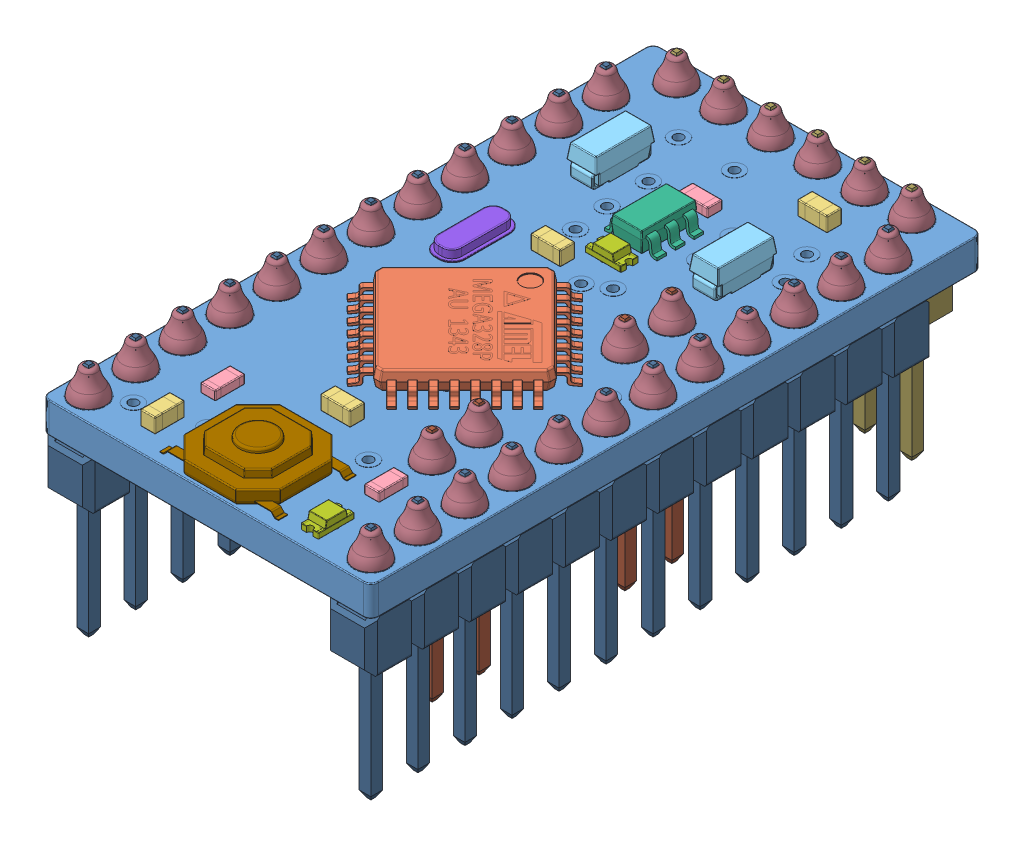
SolidWorks assembly ASSEMBLY, configuration Default. Lengths in mm.
Overall size (17.78 12.75 33.02).
56 component instances, 13 part files, 84 mates.
Components (placement in the parent):
- board-1: board [Default] at (5.4752 15.0552 41.6975) size (17.78 1.67 33.02)
- ATmega-1: ATmega [Default] at (14.3652 16.8027 27.7275) x (0.707107 0 0.707107) z (-0.707107 0 0.707107) size (9 1.1 9)
- cap_603-1: cap_603 [Default] at (10.3417 16.7052 40.4401) x (0 0 -1) z (1 0 0) size (1.6 0.8 0.8)
- cap_603-2: cap_603 [Default] at (13.6922 16.7052 34.8585) size (1.6 0.8 0.8)
- cap_603-3: cap_603 [Default] at (11.8634 16.7052 21.6759) size (1.6 0.8 0.8)
- cap_603-4: cap_603 [Default] at (17.4768 16.7052 12.8875) size (1.6 0.8 0.8)
- res_603-1: res_603 [Default] at (10.4218 16.7052 37.2651) x (0 0 -1) z (1 0 0) size (1.6 0.5 0.8)
- res_603-2: res_603 [Default] at (19.5912 16.7052 37.5953) x (0 0 -1) z (1 0 0) size (1.6 0.5 0.8)
- res_603-3: res_603 [Default] at (15.1652 16.7052 14.6275) x (-1 0 0) z (0 0 -1) size (1.6 0.5 0.8)
- condensateurTantale_106C-1: condensateurTantale_106C [Défaut] at (10.1742 17.5052 15.6625) x (0 0 -1) z (1 0 0) size (3.2 1.6 1.6)
- condensateurTantale_106C-2: condensateurTantale_106C [Défaut] at (18.6832 17.5052 17.5675) x (0 0 -1) z (1 0 0) size (3.2 1.6 1.6)
- SOT23-5-1: SOT23-5 [Default] at (14.3653 16.6848 17.5167) x (1 0 0) z (0 1 0) size (2.91 3.01 1.23)
- Surface Mount Chip LED 3.2x1.6mm-1: Surface Mount Chip LED 3.2x1.6mm [Default] at (18.7112 16.7112 39.0103) x (0 0 1) z (0 1 0) size (1.92 0.96 0.72)
- Surface Mount Chip LED 3.2x1.6mm-2: Surface Mount Chip LED 3.2x1.6mm [Default] at (13.4306 16.7112 20.3081) x (1 0 0) z (0 1 0) size (1.92 0.96 0.72)
- Crystal_Low_Profile-1: Crystal_Low_Profile [Default] at (9.717 16.7052 22.6754) x (0 0 -1) z (0 1 0) size (3.84 1.66 0.85)
  - Fusion001-1: Fusion001 [Default] at origin size (3.84 1.66 0.85)
- TACTILE-SWITCH-SMD-ALT01-1: TACTILE-SWITCH-SMD-ALT01 [Default] at (14.4922 16.7052 39.0305) size (6.4 1.4 5.25)
- Pin Header 1x12 TH Pitch 2.54mm-1: Pin Header 1x12 TH Pitch 2.54mm [Default] at (6.7452 15.0555 40.428) x (0 0.000074 -1) z (0 -1 -0.000074) size (30.48 2.54 12.7)
- Pin Header 1x12 TH Pitch 2.54mm-2: Pin Header 1x12 TH Pitch 2.54mm [Default] at (21.9852 15.0555 40.428) x (0 0.000074 -1) z (0 -1 -0.000074) size (30.48 2.54 12.7)
- Pin Header 1x2 TH Pitch 2.54mm-1: Pin Header 1x2 TH Pitch 2.54mm [Default] at (19.0642 15.0566 31.6645) x (0 0 1) z (0 -1 0) size (5.08 2.54 12.7)
- Pin Header 1x2 TH Pitch 2.54mm-2: Pin Header 1x2 TH Pitch 2.54mm [Default] at (19.0642 15.0565 21.2505) x (0 0.000074 1) z (0 -1 0.000074) size (5.08 2.54 12.7)
- Pin Header 1x6 TH Pitch 2.54mm-1: Pin Header 1x6 TH Pitch 2.54mm [Default] at (8.0152 15.0566 9.9475) x (1 0 0) z (0 -1 0) size (15.24 2.54 12.7)
- solder-1: solder [Default] at (6.7452 16.7152 40.4275) size (1.8 1.45 1.8)
- solder-13: solder [Default] at (21.9852 16.7152 40.4275) size (1.8 1.45 1.8)
- solder-25: solder [Default] at (19.0642 16.7152 23.7905) size (1.8 1.45 1.8)
- solder-37: solder [Default] at (19.0642 16.7152 34.2045) size (1.8 1.45 1.8)
- solder-39: solder [Default] at (20.7152 16.7152 9.9475) size (1.8 1.45 1.8)
- solder-2: solder [Default] at (6.7452 16.7152 37.8875) size (1.8 1.45 1.8)
- solder-3: solder [Default] at (6.7452 16.7152 35.3475) size (1.8 1.45 1.8)
- solder-4: solder [Default] at (6.7452 16.7152 32.8075) size (1.8 1.45 1.8)
- solder-5: solder [Default] at (6.7452 16.7152 30.2675) size (1.8 1.45 1.8)
- solder-6: solder [Default] at (6.7452 16.7152 27.7275) size (1.8 1.45 1.8)
- solder-7: solder [Default] at (6.7452 16.7152 25.1875) size (1.8 1.45 1.8)
- solder-8: solder [Default] at (6.7452 16.7152 22.6475) size (1.8 1.45 1.8)
- solder-9: solder [Default] at (6.7452 16.7152 20.1075) size (1.8 1.45 1.8)
- solder-10: solder [Default] at (6.7452 16.7152 17.5675) size (1.8 1.45 1.8)
- solder-11: solder [Default] at (6.7452 16.7152 15.0275) size (1.8 1.45 1.8)
- solder-12: solder [Default] at (6.7452 16.7152 12.4875) size (1.8 1.45 1.8)
- solder-14: solder [Default] at (21.9852 16.7152 37.8875) size (1.8 1.45 1.8)
- solder-15: solder [Default] at (21.9852 16.7152 35.3475) size (1.8 1.45 1.8)
- solder-16: solder [Default] at (21.9852 16.7152 32.8075) size (1.8 1.45 1.8)
- solder-17: solder [Default] at (21.9852 16.7152 30.2675) size (1.8 1.45 1.8)
- solder-18: solder [Default] at (21.9852 16.7152 27.7275) size (1.8 1.45 1.8)
- solder-19: solder [Default] at (21.9852 16.7152 25.1875) size (1.8 1.45 1.8)
- solder-20: solder [Default] at (21.9852 16.7152 22.6475) size (1.8 1.45 1.8)
- solder-21: solder [Default] at (21.9852 16.7152 20.1075) size (1.8 1.45 1.8)
- solder-22: solder [Default] at (21.9852 16.7152 17.5675) size (1.8 1.45 1.8)
- solder-23: solder [Default] at (21.9852 16.7152 15.0275) size (1.8 1.45 1.8)
- solder-24: solder [Default] at (21.9852 16.7152 12.4875) size (1.8 1.45 1.8)
- solder-26: solder [Default] at (19.0642 16.7152 21.2505) size (1.8 1.45 1.8)
- solder-38: solder [Default] at (19.0642 16.7152 31.6645) size (1.8 1.45 1.8)
- solder-40: solder [Default] at (18.1752 16.7152 9.9475) size (1.8 1.45 1.8)
- solder-41: solder [Default] at (15.6352 16.7152 9.9475) size (1.8 1.45 1.8)
- solder-42: solder [Default] at (13.0952 16.7152 9.9475) size (1.8 1.45 1.8)
- solder-43: solder [Default] at (10.5552 16.7152 9.9475) size (1.8 1.45 1.8)
- solder-44: solder [Default] at (8.0152 16.7152 9.9475) size (1.8 1.45 1.8)
Mates (geometry in assembly coordinates):
- Coincident2: coincident: plane of board-1 through (5.4752 16.7052 41.6975) normal (0 1 0); line of ATmega-1 through (9.1114 16.7052 26.6704) axis (0.707107 0 -0.707107)
- Coincident3: coincident: plane of board-1 through (5.4752 16.7052 41.6975) normal (0 1 0); line of ATmega-1 through (17.3563 16.7052 31.0474) axis (-0.707107 0 0.707107)
- Angle3: planar angle = 0.785398 rad aligned: plane of ATmega-1 through (9.6576 17.2252 26.7146) normal (-0.707107 0 -0.707107); plane of board-1 through (5.4752 16.7052 41.6975) normal (-1 0 0)
- Distance1: distance = 13.97 mm: point of ATmega-1; plane of board-1 through (5.4752 16.7052 41.6975) normal (0 0 1)
- Distance2: distance = 8.89 mm: point of ATmega-1; plane of board-1 through (5.4752 16.7052 41.6975) normal (-1 0 0)
- Parallel1: parallel aligned: plane of board-1 through (23.2552 16.7052 41.6975) normal (1 0 0); plane of cap_603-1 through (10.3417 17.5052 40.0401) normal (1 0 0)
- Distance6: distance = 4.5466 mm: point of cap_603-1; line of board-1 through (5.4752 16.6552 41.2975) axis (0 0 -1)
- Parallel2: parallel aligned: plane of board-1 through (5.4752 16.7052 41.6975) normal (0 0 1); plane of cap_603-2 through (14.0922 17.5052 34.8585) normal (0 0 1)
- Coincident11: coincident anti-aligned: plane of board-1 through (5.4752 16.7052 41.6975) normal (0 1 0); plane of cap_603-1 through (10.3417 16.7052 40.4401) normal (0 -1 0)
- Distance8: distance = 2.0574 mm: point of cap_603-1; plane of board-1 through (5.4752 16.7052 41.6975) normal (0 0 1)
- Coincident13: coincident anti-aligned: plane of board-1 through (5.4752 16.7052 41.6975) normal (0 1 0); plane of cap_603-2 through (13.6922 16.7052 34.8585) normal (0 -1 0)
- Distance9: distance = 7.239 mm: point of cap_603-2; plane of board-1 through (5.4752 16.7052 41.6975) normal (0 0 1)
- Distance10: distance = 9.017 mm: plane of board-1 through (5.4752 16.7052 41.6975) normal (-1 0 0); point of cap_603-2
- Coincident17: coincident anti-aligned: plane of board-1 through (5.4752 16.7052 41.6975) normal (0 1 0); plane of cap_603-3 through (11.8634 16.7052 21.6759) normal (0 -1 0)
- Parallel4: parallel aligned: plane of board-1 through (5.4752 16.7052 41.6975) normal (-1 0 0); plane of cap_603-3 through (11.8634 17.5052 21.6759) normal (-1 0 0)
- Distance11: distance = 7.1882 mm: point of cap_603-3; plane of board-1 through (5.4752 16.7052 41.6975) normal (-1 0 0)
- Distance12: distance = 20.4216 mm: point of cap_603-3; plane of board-1 through (5.4752 16.7052 41.6975) normal (0 0 1)
- Coincident21: coincident anti-aligned: plane of board-1 through (5.4752 16.7052 41.6975) normal (0 1 0); plane of cap_603-4 through (17.4768 16.7052 12.8875) normal (0 -1 0)
- Parallel5: parallel aligned: plane of board-1 through (5.4752 16.7052 41.6975) normal (-1 0 0); plane of cap_603-4 through (17.4768 17.5052 12.8875) normal (-1 0 0)
- Distance13: distance = 12.8016 mm: point of cap_603-4; plane of board-1 through (5.4752 16.7052 41.6975) normal (-1 0 0)
- Distance14: distance = 29.21 mm: point of cap_603-4; plane of board-1 through (5.4752 16.7052 41.6975) normal (0 0 1)
- Parallel6: parallel anti-aligned: plane of board-1 through (5.4752 16.7052 41.6975) normal (-1 0 0); plane of res_603-1 through (10.4218 17.2052 36.9651) normal (1 0 0)
- Distance15: distance = 5.2324 mm: point of res_603-1; plane of board-1 through (5.4752 16.7052 41.6975) normal (0 0 1)
- Coincident27: coincident anti-aligned: plane of board-1 through (5.4752 16.7052 41.6975) normal (0 1 0); plane of res_603-1 through (10.4218 16.7052 37.2651) normal (0 -1 0)
- Distance16: distance = 4.5466 mm: point of res_603-1; plane of board-1 through (5.4752 16.7052 41.6975) normal (-1 0 0)
- Parallel7: parallel aligned: plane of board-1 through (5.4752 16.7052 41.6975) normal (-1 0 0); plane of res_603-2 through (18.7912 17.2052 37.2953) normal (-1 0 0)
- Coincident30: coincident anti-aligned: plane of board-1 through (5.4752 16.7052 41.6975) normal (0 1 0); plane of res_603-2 through (19.5912 16.7052 37.5953) normal (0 -1 0)
- Distance17: distance = 13.716 mm: point of res_603-2; plane of board-1 through (5.4752 16.7052 41.6975) normal (-1 0 0)
- Distance18: distance = 4.9022 mm: point of res_603-2; plane of board-1 through (5.4752 16.7052 41.6975) normal (0 0 1)
- Coincident33: coincident anti-aligned: plane of board-1 through (5.4752 16.7052 41.6975) normal (0 1 0); plane of res_603-3 through (15.1652 16.7052 14.6275) normal (0 -1 0)
- Parallel9: parallel anti-aligned: plane of board-1 through (23.2552 16.7052 41.6975) normal (1 0 0); plane of res_603-3 through (13.5652 17.2052 15.4275) normal (-1 0 0)
- Distance19: distance = 8.89 mm: point of res_603-3; plane of board-1 through (5.4752 16.7052 41.6975) normal (-1 0 0)
- Distance20: distance = 26.67 mm: point of res_603-3; plane of board-1 through (5.4752 16.7052 41.6975) normal (0 0 1)
- Coincident34: coincident anti-aligned: plane of board-1 through (5.4752 16.7052 41.6975) normal (0 1 0); plane of condensateurTantale_106C-1 through (10.7742 16.7052 14.2125) normal (0 -1 0)
- Distance21: distance = 4.699 mm: point of condensateurTantale_106C-1; plane of board-1 through (5.4752 16.7052 41.6975) normal (-1 0 0)
- Distance22: distance = 26.035 mm: point of condensateurTantale_106C-1; plane of board-1 through (5.4752 16.7052 41.6975) normal (0 0 1)
- Parallel16: parallel anti-aligned: line of board-1 through (5.4752 16.6552 41.2975) axis (0 0 -1); line of condensateurTantale_106C-1 through (9.375 17.5114 14.2979) axis (0 0 1)
- Coincident42: coincident anti-aligned: plane of board-1 through (5.4752 16.7052 41.6975) normal (0 1 0); plane of condensateurTantale_106C-2 through (19.2832 16.7052 19.0175) normal (0 -1 0)
- Parallel17: parallel anti-aligned: line of board-1 through (5.4752 16.6552 41.2975) axis (0 0 -1); line of condensateurTantale_106C-2 through (17.884 17.5114 16.2029) axis (0 0 1)
- Distance23: distance = 13.208 mm: point of condensateurTantale_106C-2; plane of board-1 through (5.4752 16.7052 41.6975) normal (-1 0 0)
- Distance24: distance = 24.13 mm: point of condensateurTantale_106C-2; plane of board-1 through (5.4752 16.7052 41.6975) normal (0 0 1)
- Coincident50: coincident: plane of board-1 through (5.4752 16.7052 41.6975) normal (0 1 0); line of SOT23-5-1 through (12.9501 16.7052 16.7667) axis (0 0 -1)
- Coincident51: coincident: plane of board-1 through (5.4752 16.7052 41.6975) normal (0 1 0); line of SOT23-5-1 through (15.7804 16.7052 16.2667) axis (0 0 1)
- Parallel23: parallel aligned: line of board-1 through (5.5252 16.7052 9.0775) axis (0 0 1); line of SOT23-5-1 through (13.5402 17.5131 16.0666) axis (0 0 1)
- Distance25: distance = 8.89 mm: point of SOT23-5-1; plane of board-1 through (5.4752 16.7052 41.6975) normal (-1 0 0)
- Distance26: distance = 24.1808 mm: point of SOT23-5-1; plane of board-1 through (5.4752 16.7052 41.6975) normal (0 0 1)
- Coincident55: coincident anti-aligned: plane of board-1 through (5.4752 16.7052 41.6975) normal (0 1 0); plane of Surface Mount Chip LED 3.2x1.6mm-1 through (18.8312 16.7052 39.0103) normal (0 -1 0)
- Parallel24: parallel anti-aligned: plane of board-1 through (5.4752 16.7052 41.6975) normal (-1 0 0); plane of Surface Mount Chip LED 3.2x1.6mm-1 through (19.6712 16.7112 40.9303) normal (1 0 0)
- Distance27: distance = 1.7272 mm: point of Surface Mount Chip LED 3.2x1.6mm-1; plane of board-1 through (5.4752 16.7052 41.6975) normal (0 0 1)
- Distance28: distance = 13.716 mm: point of Surface Mount Chip LED 3.2x1.6mm-1; plane of board-1 through (5.4752 16.7052 41.6975) normal (-1 0 0)
- Coincident59: coincident anti-aligned: plane of board-1 through (5.4752 16.7052 41.6975) normal (0 1 0); plane of Surface Mount Chip LED 3.2x1.6mm-2 through (13.4306 16.7052 20.1881) normal (0 -1 0)
- Parallel25: parallel anti-aligned: plane of board-1 through (5.4752 16.7052 41.6975) normal (-1 0 0); plane of Surface Mount Chip LED 3.2x1.6mm-2 through (15.3506 16.7112 20.3081) normal (1 0 0)
- Distance29: distance = 8.9154 mm: point of Surface Mount Chip LED 3.2x1.6mm-2; plane of board-1 through (5.4752 16.7052 41.6975) normal (-1 0 0)
- Distance30: distance = 21.8694 mm: point of Surface Mount Chip LED 3.2x1.6mm-2; plane of board-1 through (5.4752 16.7052 41.6975) normal (0 0 1)
- Coincident63: coincident anti-aligned: plane of board-1 through (5.4752 16.7052 41.6975) normal (0 1 0); plane of Crystal_Low_Profile-1/Fusion001-1 through (8.9033 16.7052 24.5829) normal (0 -1 0)
- Parallel26: parallel anti-aligned: plane of board-1 through (5.4752 16.7052 41.6975) normal (-1 0 0); plane of Crystal_Low_Profile-1/Fusion001-1 through (10.347 16.7652 20.9342) normal (1 0 0)
- Distance31: distance = 4.2418 mm: point of Crystal_Low_Profile-1/Fusion001-1; plane of board-1 through (5.4752 16.7052 41.6975) normal (-1 0 0)
- Distance32: distance = 19.0246 mm: point of Crystal_Low_Profile-1/Fusion001-1; plane of board-1 through (5.4752 16.7052 41.6975) normal (0 0 1)
- Parallel27: parallel anti-aligned: line of board-1 through (5.8752 16.7052 41.6475) axis (1 0 0); line of TACTILE-SWITCH-SMD-ALT01-1 through (15.8663 17.5052 41.568) axis (-1 0 0)
- Coincident68: coincident anti-aligned: plane of board-1 through (5.4752 16.7052 41.6975) normal (0 1 0); plane of TACTILE-SWITCH-SMD-ALT01-1 through (11.4609 16.7052 40.6305) normal (0 -1 0)
- Distance33: distance = 2.667 mm: point of TACTILE-SWITCH-SMD-ALT01-1; plane of board-1 through (5.4752 16.7052 41.6975) normal (0 0 1)
- Distance34: distance = 9.017 mm: point of TACTILE-SWITCH-SMD-ALT01-1; plane of board-1 through (5.4752 16.7052 41.6975) normal (-1 0 0)
- Coincident77: coincident aligned: plane of board-1 through (5.4752 16.7052 41.6975) normal (0 0 1); plane of Pin Header 1x12 TH Pitch 2.54mm-1 through (5.8022 12.5824 41.6975) normal (0 0 1)
- Coincident78: coincident aligned: plane of board-1 through (5.4752 16.7052 41.6975) normal (-1 0 0); plane of Pin Header 1x12 TH Pitch 2.54mm-1 through (5.4752 15.0831 39.4845) normal (-1 0 0)
- Coincident79: coincident anti-aligned: plane of board-1 through (5.4752 15.0552 41.6975) normal (0 -1 0); plane of Pin Header 1x12 TH Pitch 2.54mm-1 through (5.4652 15.0552 39.6305) normal (0 1 0)
- Coincident84: coincident aligned: plane of board-1 through (5.4752 16.7052 41.6975) normal (0 0 1); plane of Pin Header 1x12 TH Pitch 2.54mm-2 through (21.0422 12.5824 41.6975) normal (0 0 1)
- Coincident85: coincident aligned: plane of board-1 through (23.2552 16.7052 41.6975) normal (1 0 0); plane of Pin Header 1x12 TH Pitch 2.54mm-2 through (23.2552 15.0831 39.4845) normal (1 0 0)
- Coincident86: coincident anti-aligned: plane of board-1 through (5.4752 15.0552 41.6975) normal (0 -1 0); plane of Pin Header 1x12 TH Pitch 2.54mm-2 through (23.2652 15.0552 39.6305) normal (0 1 0)
- Distance36: distance = 14.859 mm anti-aligned: plane of Pin Header 1x2 TH Pitch 2.54mm-1 through (20.3342 15.0832 32.608) normal (1 0 0); plane of board-1 through (5.4752 16.7052 41.6975) normal (-1 0 0)
- Coincident89: coincident anti-aligned: plane of board-1 through (5.4752 15.0552 41.6975) normal (0 -1 0); plane of Pin Header 1x2 TH Pitch 2.54mm-1 through (20.3442 15.0552 33.4075) normal (0 1 0)
- Distance38: distance = 6.223 mm aligned: plane of Pin Header 1x2 TH Pitch 2.54mm-1 through (20.0072 12.5824 35.4745) normal (0 0 1); plane of board-1 through (5.4752 16.7052 41.6975) normal (0 0 1)
- Coincident97: coincident aligned: plane of board-1 through (5.4752 16.7052 8.6775) normal (0 0 -1); plane of Pin Header 1x6 TH Pitch 2.54mm-1 through (12.1522 15.0831 8.6775) normal (0 0 -1)
- Coincident98: coincident anti-aligned: plane of board-1 through (5.4752 15.0552 41.6975) normal (0 -1 0); plane of Pin Header 1x6 TH Pitch 2.54mm-1 through (12.2982 15.0552 8.6675) normal (0 1 0)
- Distance41: distance = 16.51 mm anti-aligned: plane of Pin Header 1x6 TH Pitch 2.54mm-1 through (21.9852 12.5824 9.0045) normal (1 0 0); plane of board-1 through (5.4752 16.7052 41.6975) normal (-1 0 0)
- Coincident99: coincident anti-aligned: plane of board-1 through (6.7452 16.7152 40.4275) normal (0 1 0); plane of solder-1 through (6.7452 16.7152 40.4275) normal (0 -1 0)
- Concentric1: concentric anti-aligned: circle of board-1; circle of solder-1
- Coincident100: coincident anti-aligned: plane of board-1 through (21.9852 16.7152 40.4275) normal (0 1 0); plane of solder-13 through (21.9852 16.7152 40.4275) normal (0 -1 0)
- Concentric2: concentric anti-aligned: circle of board-1; circle of solder-13
- Concentric3: concentric anti-aligned: circle of board-1; circle of solder-25
- Coincident101: coincident anti-aligned: plane of board-1 through (19.0642 16.7152 23.7905) normal (0 1 0); plane of solder-25 through (19.0642 16.7152 23.7905) normal (0 -1 0)
- Coincident102: coincident anti-aligned: plane of board-1 through (19.0642 16.7152 34.2045) normal (0 1 0); plane of solder-37 through (19.0642 16.7152 34.2045) normal (0 -1 0)
- Concentric4: concentric anti-aligned: circle of board-1; circle of solder-37
- Coincident103: coincident anti-aligned: plane of board-1 through (20.7152 16.7152 9.9475) normal (0 1 0); plane of solder-39 through (20.7152 16.7152 9.9475) normal (0 -1 0)
- Concentric5: concentric anti-aligned: circle of board-1; circle of solder-39
